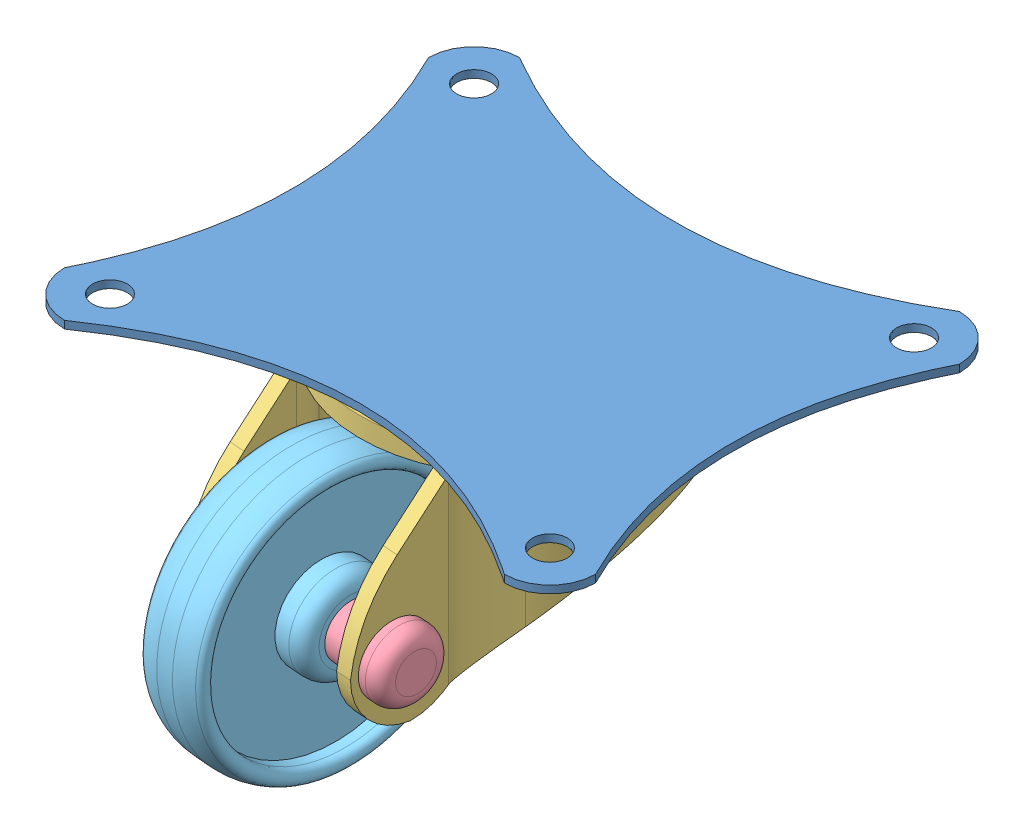
SolidWorks assembly CW-ASSEMB, configuration Default. Lengths in mm.
Overall size (35 20.04 36.76).
34 component instances, 5 part files, 7 mates.
Components (placement in the parent):
- TOP-PLATE-1: TOP-PLATE [Default] at (1.4304 25.2039 -10.3891) size (35 1.5 30)
- ball-1: ball [Default] at (-42.2153 16.0347 6.9599) x (-0.509414 -0.633944 -0.581905) z (0.514241 -0.766462 0.384827) size (1 1 1)
- ball-2: ball [Default] at (-43.5074 16.0347 6.6991) x (-0.642664 -0.633944 -0.430231) z (0.596319 -0.766462 0.23862) size (1 1 1)
- ball-3: ball [Default] at (-44.823 16.0347 6.7815) x (-0.732117 -0.633944 -0.249237) z (0.637759 -0.766462 0.07615) size (1 1 1)
- ball-4: ball [Default] at (-46.0725 16.0347 7.2017) x (-0.771679 -0.633944 -0.051259) z (0.635737 -0.766462 -0.091509) size (1 1 1)
- ball-5: ball [Default] at (-47.1706 16.0347 7.9309) x (-0.758651 -0.633944 0.150213) z (0.590391 -0.766462 -0.252932) size (1 1 1)
- ball-6: ball [Default] at (-48.0426 16.0347 8.9195) x (-0.693923 -0.633944 0.341448) z (0.50481 -0.766462 -0.397118) size (1 1 1)
- ball-7: ball [Default] at (-48.629 16.0347 10.1) x (-0.581905 -0.633944 0.509414) z (0.384827 -0.766462 -0.514241) size (1 1 1)
- ball-8: ball [Default] at (-48.8899 16.0347 11.3922) x (-0.430231 -0.633944 0.642664) z (0.23862 -0.766462 -0.596319) size (1 1 1)
- ball-9: ball [Default] at (-48.8074 16.0347 12.7078) x (-0.249237 -0.633944 0.732117) z (0.07615 -0.766462 -0.637759) size (1 1 1)
- ball-10: ball [Default] at (-48.3873 16.0347 13.9572) x (-0.051259 -0.633944 0.771679) z (-0.091509 -0.766462 -0.635737) size (1 1 1)
- ball-11: ball [Default] at (-47.6581 16.0347 15.0554) x (0.150213 -0.633944 0.758651) z (-0.252932 -0.766462 -0.590391) size (1 1 1)
- ball-12: ball [Default] at (-46.6695 16.0347 15.9274) x (0.341448 -0.633944 0.693923) z (-0.397118 -0.766462 -0.50481) size (1 1 1)
- ball-13: ball [Default] at (-45.4889 16.0347 16.5138) x (0.509414 -0.633944 0.581905) z (-0.514241 -0.766462 -0.384827) size (1 1 1)
- ball-14: ball [Default] at (-44.1968 16.0347 16.7746) x (0.642664 -0.633944 0.430231) z (-0.596319 -0.766462 -0.23862) size (1 1 1)
- ball-15: ball [Default] at (-42.8812 16.0347 16.6922) x (0.732117 -0.633944 0.249237) z (-0.637759 -0.766462 -0.07615) size (1 1 1)
- ball-16: ball [Default] at (-41.6317 16.0347 16.2721) x (0.771679 -0.633944 0.051259) z (-0.635737 -0.766462 0.091509) size (1 1 1)
- ball-17: ball [Default] at (-40.5336 16.0347 15.5428) x (0.758651 -0.633944 -0.150213) z (-0.590391 -0.766462 0.252932) size (1 1 1)
- ball-18: ball [Default] at (-39.6616 16.0347 14.5543) x (0.693923 -0.633944 -0.341448) z (-0.50481 -0.766462 0.397118) size (1 1 1)
- ball-19: ball [Default] at (-39.0752 16.0347 13.3737) x (0.581905 -0.633944 -0.509414) z (-0.384827 -0.766462 0.514241) size (1 1 1)
- ball-20: ball [Default] at (-38.8143 16.0347 12.0815) x (0.430231 -0.633944 -0.642664) z (-0.23862 -0.766462 0.596319) size (1 1 1)
- ball-21: ball [Default] at (-38.8968 16.0347 10.7659) x (0.249237 -0.633944 -0.732117) z (-0.07615 -0.766462 0.637759) size (1 1 1)
- ball-22: ball [Default] at (-39.3169 16.0347 9.5165) x (0.051259 -0.633944 -0.771679) z (0.091509 -0.766462 0.635737) size (1 1 1)
- ball-23: ball [Default] at (-40.0461 16.0347 8.4183) x (-0.150213 -0.633944 -0.758651) z (0.252932 -0.766462 0.590391) size (1 1 1)
- ball-24: ball [Default] at (-41.0347 16.0347 7.5463) x (-0.341448 -0.633944 -0.693923) z (0.397118 -0.766462 0.50481) size (1 1 1)
- ball-25: ball [Default] at (-42.2153 16.0347 6.9599) x (-0.509414 -0.633944 -0.581905) z (0.514241 -0.766462 0.384827) size (1 1 1)
- ball-26: ball [Default] at (-43.5074 16.0347 6.6991) x (-0.642664 -0.633944 -0.430231) z (0.596319 -0.766462 0.23862) size (1 1 1)
- ball-27: ball [Default] at (-44.823 16.0347 6.7815) x (-0.732117 -0.633944 -0.249237) z (0.637759 -0.766462 0.07615) size (1 1 1)
- ball-28: ball [Default] at (-46.0725 16.0347 7.2017) x (-0.771679 -0.633944 -0.051259) z (0.635737 -0.766462 -0.091509) size (1 1 1)
- ball-29: ball [Default] at (-47.1706 16.0347 7.9309) x (-0.758651 -0.633944 0.150213) z (0.590391 -0.766462 -0.252932) size (1 1 1)
- ball-30: ball [Default] at (-48.0426 16.0347 8.9195) x (-0.693923 -0.633944 0.341448) z (0.50481 -0.766462 -0.397118) size (1 1 1)
- WHEEL-CARRIER-2: WHEEL-CARRIER [Default] at (-38.8126 15.4458 12.14) x (-0.996815 0 -0.079752) z (-0.079752 0 0.996815) size (20 14.19 25)
- wheel-pin-3: wheel-pin [Default] at (-0.6345 -19.6868 23.8829) x (0.995309 -0.003159 0.0967) z (-0.09565 -0.182544 0.978534) size (15.04 4.5 4.72)
- WHEEL-3: WHEEL [Default] at (-30.6146 -23.6819 -2.8382) x (0.009615 -0.999326 -0.035433) z (-0.996773 -0.006754 -0.079993) size (18.01 18 6.03)
Mates (geometry in assembly coordinates):
- Tangent1: tangent anti-aligned: torus of TOP-PLATE-1; sphere of ball-1
- Concentric3: concentric anti-aligned: circle of TOP-PLATE-1; cylinder of WHEEL-CARRIER-2 through (-43.8521 12.8347 11.7369) axis (0 1 0) radius 2.5
- Coincident1: coincident anti-aligned: plane of TOP-PLATE-1 through (-29.3521 17.0347 11.7369) normal (0 -1 0); plane of WHEEL-CARRIER-2 through (-34.0833 17.0347 12.5184) normal (0 1 0)
- Concentric4: concentric anti-aligned: cylinder of WHEEL-CARRIER-2 through (-54.7988 6.8347 23.1701) axis (0.996815 0 0.079752) radius 1.75; cylinder of wheel-pin-3 through (-33.9158 6.8347 24.8408) axis (-0.996815 0 -0.079752) radius 1.75
- Coincident2: coincident anti-aligned: plane of WHEEL-CARRIER-2 through (-49.0353 12.8347 1.2882) normal (-0.996815 0 -0.079752); plane of wheel-pin-3 through (-50.8115 6.8347 23.4891) normal (0.996815 0 0.079752)
- Concentric5: concentric anti-aligned: cylinder of wheel-pin-3 through (-33.9158 6.8347 24.8408) axis (-0.996815 0 -0.079752) radius 1.75; cylinder of WHEEL-3 through (-47.8211 6.8347 23.7283) axis (0.996815 0 0.079752) radius 1.75
- Distance1: distance = 2 mm anti-aligned: plane of WHEEL-3 through (-41.8402 6.8347 24.2068) normal (0.996815 0 0.079752); plane of WHEEL-CARRIER-2 through (-38.0703 12.8347 2.1655) normal (-0.996815 0 -0.079752)
